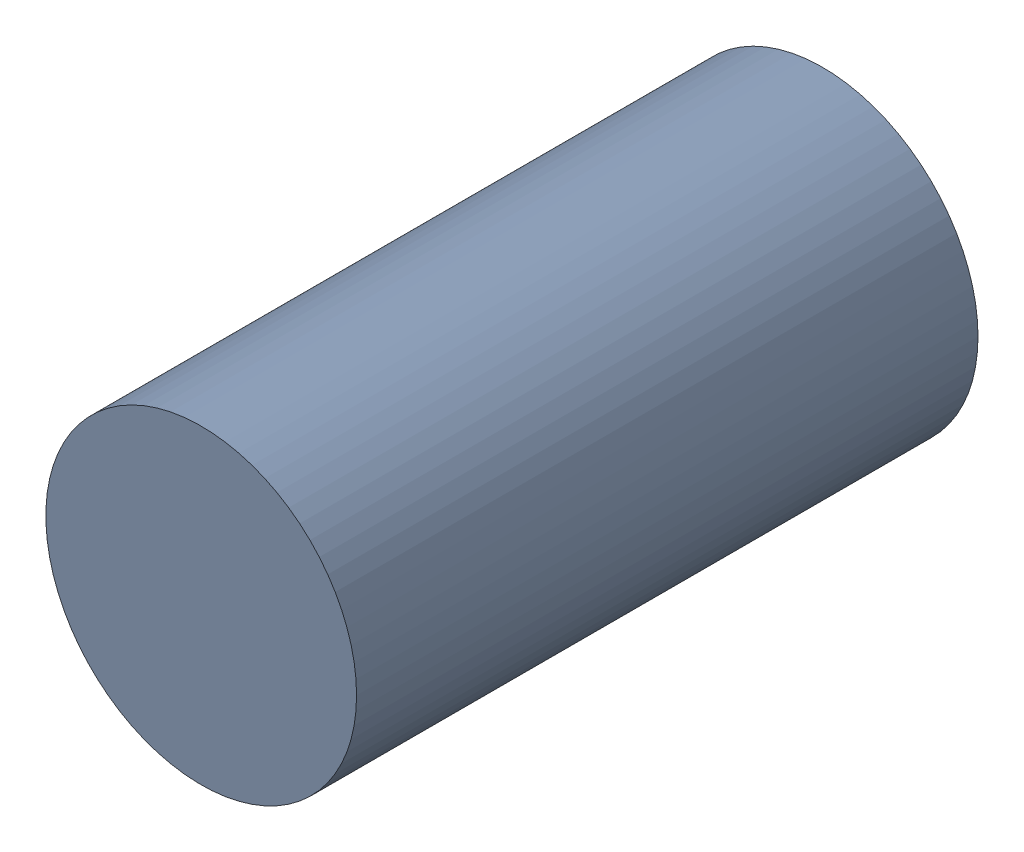
SolidWorks assembly MH12_2.step, configuration Default. Lengths in mm.
Overall size (1 1 2).
2 component instances, 1 part files, 0 mates.
Components (placement in the parent):
- 9228463120_2.step-2: 9228463120_2.step [Default] at (138.498 92.1677 -1.5) size (1 1 2)
  - Cylinder_4.step-7: Cylinder_4.step [Default] at origin size (1 1 2)
